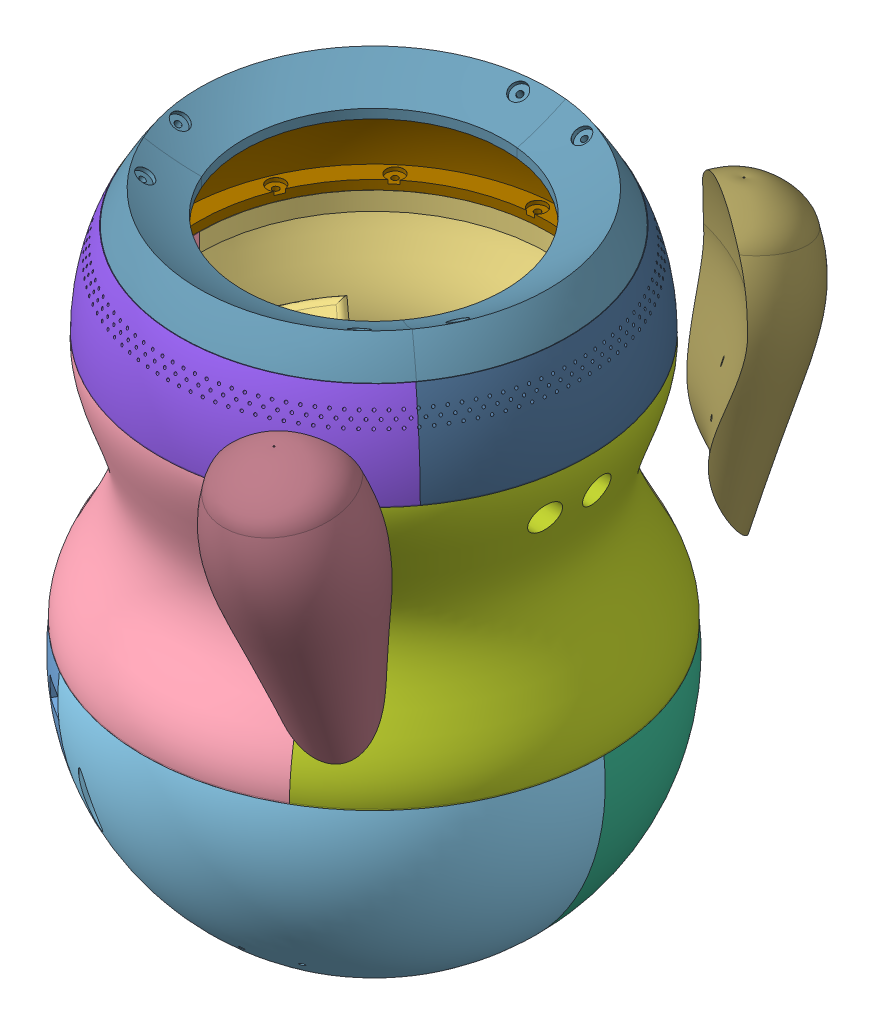
SolidWorks assembly bodyAssembly, configuration Défaut. Lengths in mm.
Overall size (318.22 585.46 348.54).
16 component instances, 14 part files, 28 mates.
Components (placement in the parent):
- body_bottom_back-3: body_bottom_back [Défaut] at (77.8148 3.5849 0.3337) x (0.049646 0 -0.998767) z (0.998767 0 0.049646) size (218.81 181.14 229.88)
- hood_bottom-1: hood_bottom [Défaut] at (88.5251 -95.0219 0) x (-0.865075 0 0.501643) z (0.501643 0 0.865075) size (99.91 75.51 99.91)
- body_middle_handle_left-1: body_middle_handle_left [Défaut] at (84.0876 21.8675 -7.018) x (0.889771 0 -0.456408) z (0.456408 0 0.889771) size (219.58 137 233.1)
- body_middle_handle_right-1: body_middle_handle_right [Défaut] at (84.0879 21.8675 7.0182) x (0.88979 0 0.456369) z (-0.456369 0 0.88979) size (219.58 137 101.96)
- body_bottom_left-1: body_bottom_left [Défaut] at (94.1692 3.5849 9.1085) x (-0.889781 0 0.456388) z (-0.456388 0 -0.889781) size (218.17 119.6 229.88)
- body_bottom_right-1: body_bottom_right [Défaut] at (93.5912 3.5849 -9.4422) x (0.840134 0 0.542378) z (-0.542378 0 0.840134) size (218.17 119.6 229.88)
- body_middle_front-1: body_middle_front [Défaut] at (96.8216 21.8675 -0.3339) x (-0.049625 0 0.998768) z (-0.998768 0 -0.049625) size (219.58 137 233.1)
- body_top_left-1: body_top_left [Défaut] at (87.7005 20.6082 10.6911) x (-0.987582 0 -0.157104) z (0.157104 0 -0.987582) size (205.58 215.16 224.44)
- body_top_middle-1: body_top_middle [Défaut] at (79.6784 20.6076 -6.0594) x (0.629847 0 -0.776719) z (0.776719 0 0.629847) size (205.58 215.16 224.44)
- body_top_right-1: body_top_right [Défaut] at (98.196 20.6076 -4.6317) x (0.357735 0 0.933823) z (-0.933823 0 0.357735) size (205.58 215.16 224.44)
- hood_top-1: hood_top [Défaut] at (88.5251 15.8089 0) x (0.889337 0 -0.457252) z (-0.457252 0 -0.889337) size (168.25 11.5 168.25)
- right_arm-1: right_arm [Défaut] at (112.1996 28.4675 -37.1902) x (-0.23281 0 -0.972522) z (0.972522 0 -0.23281) size (99.49 162.31 86.07)
- left_arm-1: left_arm [Défaut] at (107.8819 25.216 31.1666) x (0.235659 0 -0.971836) z (0.971836 0 0.235659) size (116.38 164.79 102.42)
- body_top_hood-1: body_top_hood [Défaut] at (87.7413 20.6076 10.5995) x (-0.988027 0 -0.15428) z (0.15428 0 -0.988027) size (204.12 402.34 224.44)
- body_top_hood-4: body_top_hood [Défaut] at (79.7375 20.6076 -5.9785) x (0.627624 0 -0.778517) z (0.778517 0 0.627624) size (204.12 402.34 224.44)
- body_top_hood-5: body_top_hood [Défaut] at (98.0964 20.6076 -4.621) x (0.360404 0 0.932796) z (-0.932796 0 0.360404) size (204.12 402.34 224.44)
Mates (geometry in assembly coordinates):
- Coïncidente47: coincident aligned: plane of body_middle_handle_left-1 through (-87.7625 21.5589 -65.6678) normal (0 -1 0); plane of body_middle_handle_right-1 through (-87.7597 21.5589 65.6754) normal (0 -1 0)
- Coïncidente49: coincident anti-aligned: plane of body_middle_handle_left-1 through (-37.5906 -227.2719 0.0027) normal (0.000022 0 1); plane of body_middle_handle_right-1 through (-37.5906 -227.2719 0.0027) normal (-0.000022 0 -1)
- Coïncidente53: coincident aligned: plane of body_bottom_back-3 through (88.5251 -98.0411 0) normal (0 -1 0); plane of body_bottom_right-1 through (88.5251 -98.0411 0) normal (0 -1 0)
- Coïncidente54: coincident anti-aligned: circle of body_bottom_back-3; circle of body_bottom_right-1
- Coïncidente56: coincident anti-aligned: plane of body_bottom_back-3 through (25.4672 -227.2719 109.2194) normal (0.866025 0 0.5); plane of body_bottom_left-1 through (88.5251 -227.2719 0) normal (-0.866025 0 -0.5)
- Coïncidente57: coincident aligned: plane of body_bottom_back-3 through (-32.1193 21.5589 -129.5887) normal (0 1 0); plane of body_bottom_left-1 through (36.6202 21.5589 169.2754) normal (0 1 0)
- Coïncidente58: coincident anti-aligned: circle of body_bottom_back-3; circle of body_bottom_left-1
- Coaxiale24: concentric aligned: cylinder of hood_bottom-1 through (88.5251 -86.9919 0) axis (0 -1 0) radius 32.53; cylinder of body_bottom_left-1 through (88.5251 -80.6469 0) axis (0 -1 0) radius 32.534
- Coïncidente65: coincident anti-aligned: plane of hood_bottom-1 through (88.5251 -95.0219 0) normal (0 1 0); plane of body_bottom_right-1 through (88.5251 -95.0219 0) normal (0 -1 0)
- Coïncidente67: coincident anti-aligned: plane of body_middle_handle_right-1 through (88.5251 -227.2719 0) normal (0.866015 0 -0.500019); plane of body_middle_front-1 through (88.5251 -227.2719 0) normal (-0.866015 0 0.500019)
- Coïncidente68: coincident anti-aligned: circle of body_bottom_right-1; circle of body_middle_front-1
- Coïncidente71: coincident anti-aligned: circle of body_middle_handle_left-1; circle of body_middle_handle_right-1
- Coïncidente81: coincident anti-aligned: plane of body_middle_front-1 through (221.4884 158.5589 -118.2927) normal (0 1 0); plane of body_top_middle-1 through (-83.9637 158.5589 11.1871) normal (0 -1 0)
- Coaxiale28: concentric anti-aligned: circle of body_middle_front-1; circle of body_top_middle-1
- Coïncidente82: coincident anti-aligned: plane of body_top_middle-1 through (88.5251 -227.2719 0) normal (0.994164 0 0.10788); plane of body_top_right-1 through (102.1305 -227.2719 -125.3797) normal (-0.994164 0 -0.10788)
- Coïncidente85: coincident aligned: plane of body_top_middle-1 through (-10.2717 209.0415 59.1444) normal (0 1 0); plane of body_top_right-1 through (86.7029 209.0415 -115.1328) normal (0 1 0)
- Coïncidente86: coincident anti-aligned: circle of body_top_middle-1; circle of body_top_right-1
- Coïncidente87: coincident aligned: circle of body_top_left-1; circle of body_top_right-1
- Coïncidente88: coincident anti-aligned: circle of body_top_left-1; circle of body_top_right-1
- Coaxiale32: concentric aligned: circle of body_bottom_right-1; circle of hood_top-1
- Coïncidente93: coincident anti-aligned: plane of body_top_middle-1 through (-10.2717 209.0415 59.1444) normal (0 1 0); plane of body_top_hood-1 through (194.956 209.0415 49.4558) normal (0 -1 0)
- Coïncidente97: coincident anti-aligned: plane of body_top_right-1 through (86.7029 209.0415 -115.1328) normal (0 1 0); plane of body_top_hood-4 through (-7.5203 209.0415 67.444) normal (0 -1 0)
- Coaxiale47: concentric anti-aligned: circle of body_top_right-1; circle of body_top_hood-4
- Coaxiale48: concentric anti-aligned: circle of body_top_right-1; circle of body_top_hood-1
- Coïncidente100: coincident anti-aligned: plane of body_top_hood-1 through (88.5251 -227.9015 0) normal (-0.406269 0 -0.913753); plane of body_top_hood-4 through (-26.7136 -227.9015 51.2369) normal (0.406269 0 0.913753)
- Coaxiale50: concentric anti-aligned: circle of body_top_right-1; circle of body_top_hood-5
- Coïncidente104: coincident anti-aligned: plane of body_top_hood-4 through (88.5251 -227.9015 0) normal (0.994468 0 0.105037); plane of body_top_hood-5 through (101.772 -227.9015 -125.4181) normal (-0.994468 0 -0.105037)
- Coïncidente105: coincident anti-aligned: plane of body_top_right-1 through (86.7029 209.0415 -115.1328) normal (0 1 0); plane of body_top_hood-5 through (78.1396 209.0415 -116.8997) normal (0 -1 0)
